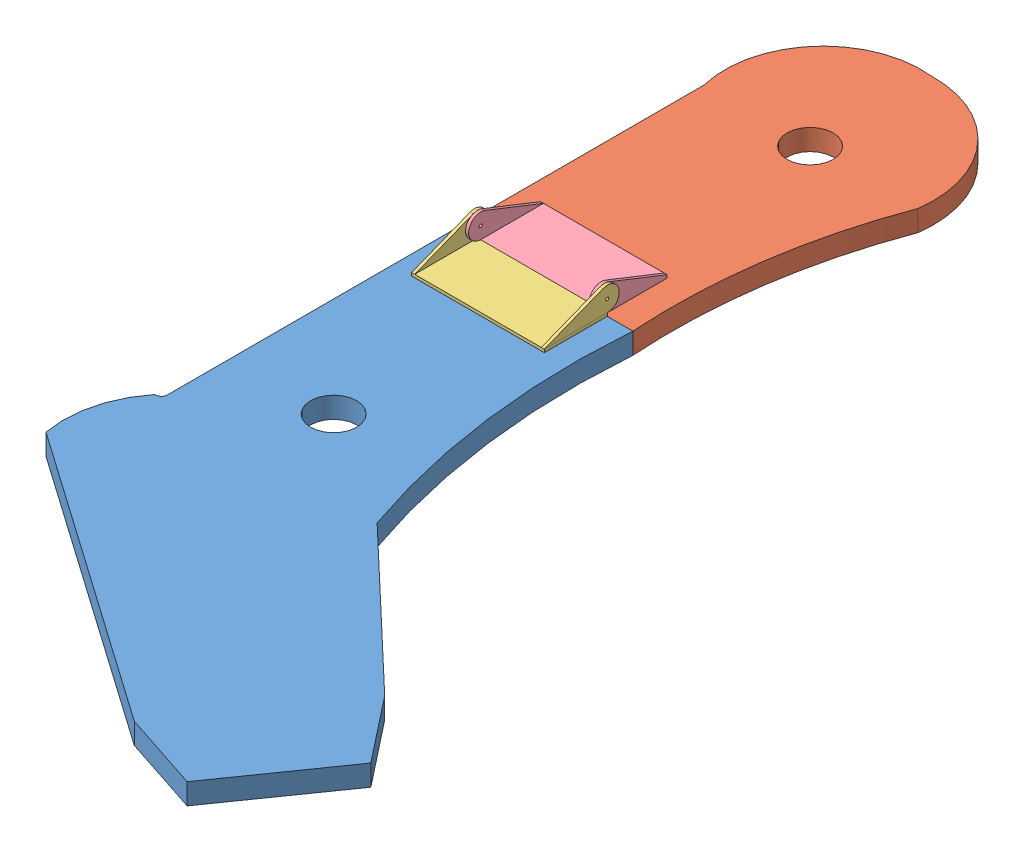
SolidWorks assembly LiftArmPaddleRight, configuration Default. Lengths in mm.
Overall size (238.84 25.41 521.17).
4 component instances, 4 part files, 7 mates.
Components (placement in the parent):
- liftArmLower-1: liftArmLower [Default] at (0.282 201.1124 91.9918) size (238.84 11.11 324.8)
- liftArmUpper-1: liftArmUpper [Default] at (9.4101 201.1504 -39.7762) x (1 0 0) z (0 -0.000288 1) size (115.4 11.11 196.36)
- hingPart-1: hingPart [Default] at (-36.0629 212.2249 124.9135) x (0 0 -1) z (1 0 0) size (39.69 14.29 70.3)
- hingPartTwo-1: hingPartTwo [Default] at (49.3335 212.2322 66.7568) x (0 0.000288 -1) z (1 0 0) size (39.69 14.29 67.07)
Mates (geometry in assembly coordinates):
- Coincident2: coincident aligned: circle of hingPart-1; circle of hingPartTwo-1
- Coincident3: coincident anti-aligned: plane of liftArmLower-1 through (-49.9227 212.2249 244.5902) normal (0 1 0); plane of hingPart-1 through (-36.0629 212.2249 124.9135) normal (0 -1 0)
- Coincident4: coincident aligned: line of liftArmLower-1 through (47.3117 212.2249 91.9918) axis (-1 0 0); line of hingPart-1 through (33.7123 212.2249 91.9918) axis (-1 0 0)
- Coincident5: coincident aligned: line of liftArmUpper-1 through (-46.7477 212.2249 91.9895) axis (1 0 0); line of hingPartTwo-1 through (-35.0002 212.2249 91.9895) axis (1 0 0)
- Coincident6: coincident anti-aligned: plane of liftArmUpper-1 through (3.7577 212.2665 -52.3313) normal (0 1 0.000288); plane of hingPartTwo-1 through (49.3335 212.2322 66.7568) normal (0 -1 -0.000288)
- Coincident8: coincident aligned: plane of liftArmLower-1 through (-46.7477 212.2249 91.9918) normal (-1 0 0); plane of liftArmUpper-1 through (-46.7477 212.2629 -39.773) normal (-1 0 0)
- Distance1: distance = 10.16 mm aligned: plane of hingPart-1 through (-36.5877 213.8124 125.3293) normal (-1 0 0); plane of liftArmLower-1 through (-46.7477 212.2249 91.9918) normal (-1 0 0)
